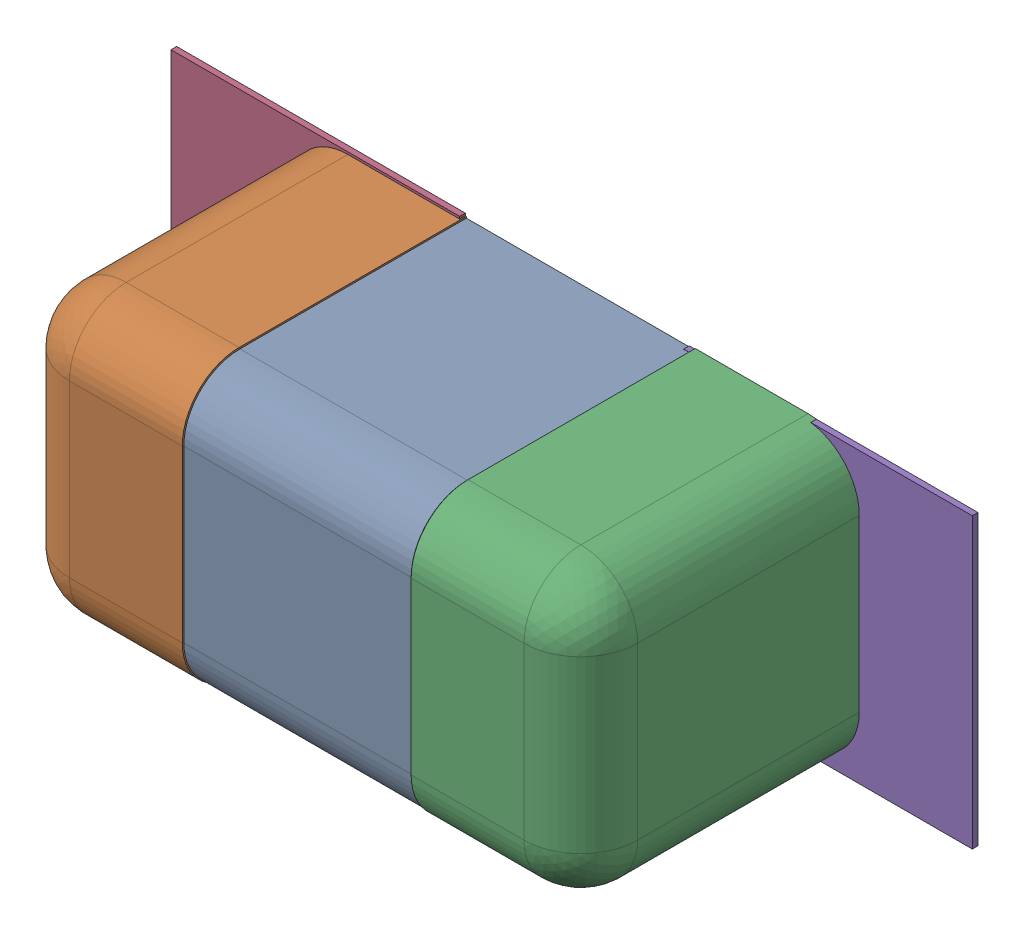
SolidWorks assembly C56, configuration Défaut. Lengths in mm.
Overall size (1.41 0.51 0.5).
8 component instances, 4 part files, 0 mates.
Components (placement in the parent):
- 6324936752-1: 6324936752 [Défaut] at (20.0795 -28.1474 0) x (1 0 0) z (0 -1 0) size (1 0.5 0.5)
  - Open CASCADE STEP translator 7.5 2.114.1.1-1: Open CASCADE STEP translator 7.5 2.114.1.1 [Défaut] at origin size (0.4 0.5 0.5)
  - Open CASCADE STEP translator 7.5 2.114.1.2-1: Open CASCADE STEP translator 7.5 2.114.1.2 [Défaut] at origin size (0.3 0.5 0.5)
  - Open CASCADE STEP translator 7.5 2.114.1.3-1: Open CASCADE STEP translator 7.5 2.114.1.3 [Défaut] at origin size (0.3 0.5 0.5)
- 6504207776-1: 6504207776 [Défaut] at (19.6222 -28.1474 0) size (0.51 0.51 0.01)
  - Extruded-1: Extruded [Défaut] at origin size (0.51 0.51 0.01)
- 6504207776-2: 6504207776 [Défaut] at (20.5245 -28.1526 0) size (0.51 0.51 0.01)
  - Extruded-1: Extruded [Défaut] at origin size (0.51 0.51 0.01)
